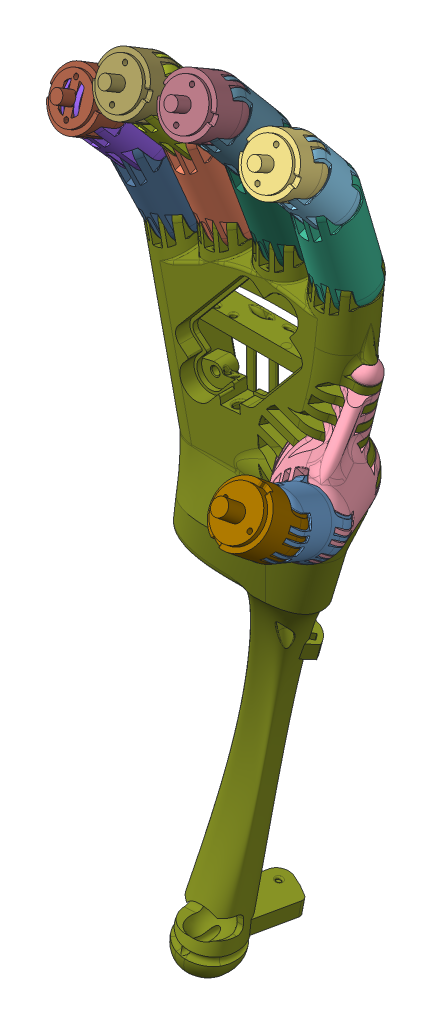
SolidWorks assembly a-hand-rechts-step-v01-oa0, configuration Standard. Lengths in mm.
Overall size (110.81 274.79 101.97).
16 component instances, 16 part files, 30 mates.
Components (placement in the parent):
- p-daumen-seg-2-step-v01-1: p-daumen-seg-2-step-v01 [Standard] at (33.2419 21.3452 28) x (-0.335915 -0.743762 0.577909) z (-0.896565 0.440536 0.045828) size (20.69 43.22 21.88)
- p-ringfinger-seg-1-step-v02-1: p-ringfinger-seg-1-step-v02 [Standard] at (-12.7428 17.6388 -17.8902) x (0.994522 0.104528 0) z (0.035751 -0.340147 0.939693) size (19.08 47.31 19.03)
- p-zeigfinger-seg-3-step-v02-1: p-zeigfinger-seg-3-step-v02 [Standard] at (15.5674 44.5129 -91.9113) x (0.994522 -0.104528 0) z (-0.090524 -0.861281 0.5) size (19.01 23.27 19)
- p-daumen-seg-1-step-v01-1: p-daumen-seg-1-step-v01 [Standard] at (11.6667 9.3333 0) x (0.090387 -0.785385 0.612372) z (-0.813798 0.296198 0.5) size (50.99 61.47 24.87)
- p-zeigfinger-seg-2-step-v02-1: p-zeigfinger-seg-2-step-v02 [Standard] at (8.7304 -20.5367 -87.9966) x (0.994522 -0.104528 0) z (-0.06719 -0.639266 0.766044) size (19.2 35.59 19.73)
- p-zeigfinger-seg-1-step-v02-1: p-zeigfinger-seg-1-step-v02 [Standard] at (12.8427 18.5894 -17.8254) x (0.994522 -0.104528 0) z (-0.035751 -0.340147 0.939693) size (19.08 48.86 19.03)
- p-ringfinger-seg-2-step-v02-1: p-ringfinger-seg-2-step-v02 [Standard] at (-8.5153 -22.5832 -88.3762) x (0.994522 0.104528 0) z (0.06719 -0.639266 0.766044) size (19.2 37.93 19.73)
- p-kleinerfinger-seg-2-step-v02-1: p-kleinerfinger-seg-2-step-v02 [Standard] at (-20.1072 -7.5356 -67.7998) x (0.976296 0.21644 0) z (0.139125 -0.627551 0.766044) size (19.1 34.83 19.68)
- p-daumen-seg-3-v01-1: p-daumen-seg-3-v01 [Standard] at (39.9777 33.0758 47.0123) x (-0.035377 0.623091 0.781348) z (-0.941228 0.242022 -0.235618) size (28.23 20.09 20.4)
- p-kleinerfinger-seg-1-step-v02-1: p-kleinerfinger-seg-1-step-v02 [Standard] at (-23.9615 9.8501 -18.4087) x (0.976296 0.21644 0) z (0.074027 -0.333913 0.939693) size (19.08 41.2 19.03)
- p-kleinerfinger-seg-3-step-v02-1: p-kleinerfinger-seg-3-step-v02 [Standard] at (-27.0329 23.7045 -104.725) x (0.976296 0.21644 0) z (0.187442 -0.845497 0.5) size (18.67 21.72 17.82)
- p-ringfinger-seg-3-step-v02-1: p-ringfinger-seg-3-step-v02 [Standard] at (-15.4056 42.9733 -92.8418) x (0.994522 0.104528 0) z (0.090524 -0.861281 0.5) size (19.01 23.27 19)
- p-mittelfinger-seg-3-step-v02-1: p-mittelfinger-seg-3-step-v02 [Standard] at (0 68.8301 -56.9189) x (1 0 0) z (0 -0.866025 0.5) size (19.01 24.05 19)
- p-mittelfinger-seg-2-step-v02-1: p-mittelfinger-seg-2-step-v02 [Standard] at (0 52.3745 -28.6799) x (1 0 0) z (0 -0.642788 0.766044) size (19.2 39.53 19.78)
- p-mittelfinger-seg-1-step-v02-1: p-mittelfinger-seg-1-step-v02 [Standard] at (0 -15.4293 -31.0937) x (1 0 0) z (0 -0.34202 0.939693) size (19.08 48.86 19.03)
- p-handfläche-teil-2-v01-1: p-handfläche-teil-2-v01 [Standard] at origin size (71.11 221.99 39.87)
Mates (geometry in assembly coordinates):
- Konzentrisch1: concentric aligned: cylinder of p-daumen-seg-2-step-v01-1 through (63.2501 17.6317 -31.0879) axis (0.028328 0.855715 0.516671) radius 3; cylinder of p-daumen-seg-3-v01-1 through (63.2586 17.8884 -30.9329) axis (0.028328 0.855715 0.516671) radius 3.3
- Abstand1: distance = 0.3 mm anti-aligned: plane of p-daumen-seg-3-v01-1 through (50.5148 22.9384 -26.9853) normal (-0.028328 -0.855715 -0.516671); plane of p-daumen-seg-2-step-v01-1 through (64.488 29.777 -39.6582) normal (0.028328 0.855715 0.516671)
- Konzentrisch2: concentric aligned: cylinder of p-daumen-seg-2-step-v01-1 through (44.9633 10.0642 -18.7133) axis (0.028328 0.855715 0.516671) radius 3.3; cylinder of p-daumen-seg-1-step-v01-1 through (45.4307 24.1835 -10.1882) axis (0.028328 0.855715 0.516671) radius 3.6
- Abstand2: distance = 0.3 mm anti-aligned: plane of p-daumen-seg-2-step-v01-1 through (49.1064 26.119 -27.5307) normal (0.028328 0.855715 0.516671); plane of p-daumen-seg-1-step-v01-1 through (29.7749 20.7868 -17.059) normal (-0.028328 -0.855715 -0.516671)
- Konzentrisch3: concentric aligned: cylinder of p-daumen-seg-1-step-v01-1 through (23.9794 43.1623 0) axis (-0.34202 -0.939693 0) radius 1; cylinder of p-handfläche-teil-2-v01-1 through (23.8768 42.8804 0) axis (-0.34202 -0.939693 0) radius 1.3
- Abstand3: distance = 0.3 mm anti-aligned: plane of p-daumen-seg-1-step-v01-1 through (20.9062 40.769 -4.114) normal (0.34202 0.939693 0); plane of p-handfläche-teil-2-v01-1 through (28.9443 38.1627 -15) normal (-0.34202 -0.939693 0)
- Konzentrisch4: concentric aligned: cylinder of p-zeigfinger-seg-3-step-v02-1 through (31.2167 112.0882 -17.0652) axis (-0.994522 0.104528 0) radius 3.05; cylinder of p-zeigfinger-seg-2-step-v02-1 through (29.2276 112.2972 -17.0652) axis (-0.994522 0.104528 0) radius 3.35
- Abstand4: distance = 0.3 mm anti-aligned: plane of p-zeigfinger-seg-2-step-v02-1 through (16.8241 118.6537 -27.9853) normal (-0.994522 0.104528 0); plane of p-zeigfinger-seg-3-step-v02-1 through (14.7837 102.1108 -14.0651) normal (0.994522 -0.104528 0)
- Abstand5: distance = 0.3 mm anti-aligned: plane of p-zeigfinger-seg-2-step-v02-1 through (13.1051 86.1402 -15.8871) normal (0.994522 -0.104528 0); plane of p-zeigfinger-seg-1-step-v02-1 through (15.0673 101.9392 -21.7948) normal (-0.994522 0.104528 0)
- Konzentrisch5: concentric aligned: cylinder of p-zeigfinger-seg-2-step-v02-1 through (29.4628 95.4011 -10.862) axis (-0.994522 0.104528 0) radius 3.05; cylinder of p-zeigfinger-seg-1-step-v02-1 through (27.4737 95.6102 -10.862) axis (-0.994522 0.104528 0) radius 3.35
- Abstand6: distance = 0.3 mm anti-aligned: plane of p-handfläche-teil-2-v01-1 through (12.3861 76.4289 -8.5) normal (-0.994522 0.104528 0); plane of p-zeigfinger-seg-1-step-v02-1 through (10.0564 57.1339 -4.9975) normal (0.994522 -0.104528 0)
- Konzentrisch6: concentric anti-aligned: cylinder of p-zeigfinger-seg-1-step-v02-1 through (26.4154 66.4075 0) axis (-0.994522 0.104528 0) radius 3.05; cylinder of p-handfläche-teil-2-v01-1 through (24.4264 66.6165 0) axis (0.994522 -0.104528 0) radius 3.35
- Konzentrisch7: concentric anti-aligned: cylinder of p-mittelfinger-seg-3-step-v02-1 through (8.5 121.8559 -10.4006) axis (-1 0 0) radius 3.05; circle of p-mittelfinger-seg-2-step-v02-1
- Abstand7: distance = 0.3 mm anti-aligned: plane of p-mittelfinger-seg-2-step-v02-1 through (-6.5 128.5539 -20.3824) normal (-1 0 0); plane of p-mittelfinger-seg-3-step-v02-1 through (-6.8 109.9854 -8.5055) normal (1 0 0)
- Abstand8: distance = 0.3 mm anti-aligned: plane of p-mittelfinger-seg-2-step-v02-1 through (-6.8 90.5065 -12.8918) normal (1 0 0); plane of p-mittelfinger-seg-1-step-v02-1 through (-6.5 107.1259 -16.2159) normal (-1 0 0)
- Konzentrisch8: concentric aligned: cylinder of p-mittelfinger-seg-2-step-v02-1 through (8.5 100.4883 -6.1938) axis (-1 0 0) radius 3.05; cylinder of p-mittelfinger-seg-1-step-v02-1 through (6.5 100.4883 -6.1938) axis (-1 0 0) radius 3.35
- Abstand9: distance = 0.3 mm anti-aligned: plane of p-mittelfinger-seg-1-step-v02-1 through (-4.5 76.9316 -10.0818) normal (-1 0 0); plane of p-handfläche-teil-2-v01-1 through (-4.8 40 -8.5) normal (1 0 0)
- Konzentrisch9: concentric anti-aligned: cylinder of p-mittelfinger-seg-1-step-v02-1 through (8.5 70 0) axis (-1 0 0) radius 3.05; cylinder of p-handfläche-teil-2-v01-1 through (6.5 70 0) axis (1 0 0) radius 3.35
- Abstand10: distance = 0.3 mm anti-aligned: plane of p-ringfinger-seg-2-step-v02-1 through (-30.1192 120.7798 22.0595) normal (-0.994522 -0.104528 0); plane of p-ringfinger-seg-3-step-v02-1 through (-29.491 111.9331 11.496) normal (0.994522 0.104528 0)
- Konzentrisch10: concentric aligned: cylinder of p-ringfinger-seg-2-step-v02-1 through (-15.9386 110.2292 23.1072) axis (-0.994522 -0.104528 0) radius 3.35; cylinder of p-ringfinger-seg-3-step-v02-1 through (-13.9496 110.4382 23.1072) axis (-0.994522 -0.104528 0) radius 3.05
- Konzentrisch11: concentric aligned: cylinder of p-ringfinger-seg-1-step-v02-1 through (-14.3194 94.8229 10.1086) axis (-0.994522 -0.104528 0) radius 3.35; cylinder of p-ringfinger-seg-2-step-v02-1 through (-12.3303 95.0319 10.1086) axis (-0.994522 -0.104528 0) radius 3.05
- Abstand11: distance = 0.3 mm anti-aligned: plane of p-ringfinger-seg-1-step-v02-1 through (-28.3869 104.2989 5.0284) normal (-0.994522 -0.104528 0); plane of p-ringfinger-seg-2-step-v02-1 through (-27.437 92.3907 -1.8665) normal (0.994522 0.104528 0)
- Abstand12: distance = 0.3 mm anti-aligned: plane of p-handfläche-teil-2-v01-1 through (-19.5185 36.1851 -8.5) normal (0.994522 0.104528 0); plane of p-ringfinger-seg-1-step-v02-1 through (-23.5243 77.1673 -4.9776) normal (-0.994522 -0.104528 0)
- Konzentrisch12: concentric anti-aligned: cylinder of p-ringfinger-seg-1-step-v02-1 through (-9.4272 67.411 0) axis (-0.994522 -0.104528 0) radius 3.05; cylinder of p-handfläche-teil-2-v01-1 through (-11.4163 67.2019 0) axis (0.994522 0.104528 0) radius 3.35
- Abstand13: distance = 0.3 mm anti-aligned: plane of p-kleinerfinger-seg-3-step-v02-1 through (-38.7713 97.4437 7.3681) normal (0.976296 0.21644 0); plane of p-kleinerfinger-seg-2-step-v02-1 through (-40.3969 106.1623 17.9316) normal (-0.976296 -0.21644 0)
- Konzentrisch13: concentric aligned: cylinder of p-kleinerfinger-seg-2-step-v02-1 through (-36.1453 94.8391 18.9793) axis (-0.976296 -0.21644 0) radius 3.35; cylinder of p-kleinerfinger-seg-3-step-v02-1 through (-34.1927 95.2719 18.9793) axis (-0.976296 -0.21644 0) radius 3.05
- Konzentrisch14: concentric aligned: cylinder of p-kleinerfinger-seg-2-step-v02-1 through (-31.3556 82.4748 7.9805) axis (-0.976296 -0.21644 0) radius 3.05; cylinder of p-kleinerfinger-seg-1-step-v02-1 through (-33.3082 82.0419 7.9805) axis (-0.976296 -0.21644 0) radius 3.35
- Abstand14: distance = 0.3 mm anti-aligned: plane of p-kleinerfinger-seg-1-step-v02-1 through (-48.3581 89.8645 2.9003) normal (-0.976296 -0.21644 0); plane of p-kleinerfinger-seg-2-step-v02-1 through (-46.0662 78.1404 -3.9946) normal (0.976296 0.21644 0)
- Konzentrisch15: concentric anti-aligned: cylinder of p-kleinerfinger-seg-1-step-v02-1 through (-26.6099 61.0684 0) axis (-0.976296 -0.21644 0) radius 3.05; cylinder of p-handfläche-teil-2-v01-1 through (-28.5625 60.6355 0) axis (0.976296 0.21644 0) radius 3.35
- Abstand15: distance = 0.3 mm anti-aligned: plane of p-handfläche-teil-2-v01-1 through (-43.0941 66.1203 -8.5) normal (-0.976296 -0.21644 0); plane of p-kleinerfinger-seg-1-step-v02-1 through (-40.4477 52.797 -10.8946) normal (0.976296 0.21644 0)
